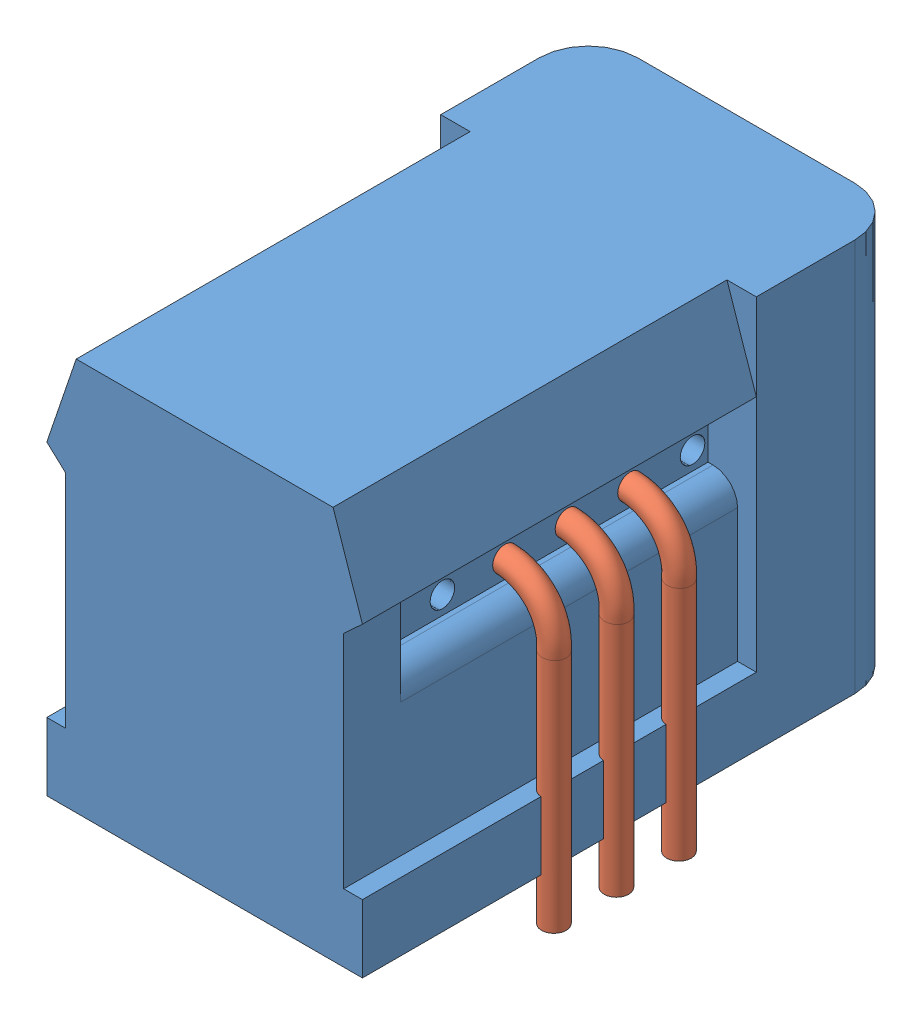
SolidWorks assembly CAS-6-NP, configuration Défaut. Lengths in mm.
Overall size (13.9 18.96 22).
7 component instances, 2 part files, 2 mates.
Components (placement in the parent):
- CAS-6-NP_boitier-1: CAS-6-NP_boitier [Défaut] at (-2.8796 -5.944 -6.9648) size (12.82 18.96 22)
- fils-1: fils [Défaut] at (1.5697 -8.0411 1.2852) x (0 0 -1) z (1 0 0) size (1 12.34 2.5)
- fils-2: fils [Défaut] at (1.5697 -8.0411 -1.2548) x (0 0 -1) z (1 0 0) size (1 12.34 2.5)
- fils-3: fils [Défaut] at (1.5697 -8.0411 -3.7948) x (0 0 -1) z (1 0 0) size (1 12.34 2.5)
- fils-4: fils [Défaut] at (-7.3289 -8.0411 1.2852) x (0 0 1) z (-1 0 0) size (1 12.34 2.5)
- fils-5: fils [Défaut] at (-7.3289 -8.0411 -1.2548) x (0 0 1) z (-1 0 0) size (1 12.34 2.5)
- fils-6: fils [Défaut] at (-7.3289 -8.0411 -3.7948) x (0 0 1) z (-1 0 0) size (1 12.34 2.5)
Mates (geometry in assembly coordinates):
- Parallèle2: parallel anti-aligned: line of CAS-6-NP_boitier-1 through (2.7697 -3.1874 9.0352) axis (0 1 0); line of fils-1 through (3.7677 1.1874 3.7592) axis (0 -1 0)
- Coïncidente2: coincident aligned: circle of CAS-6-NP_boitier-1; circle of fils-1
